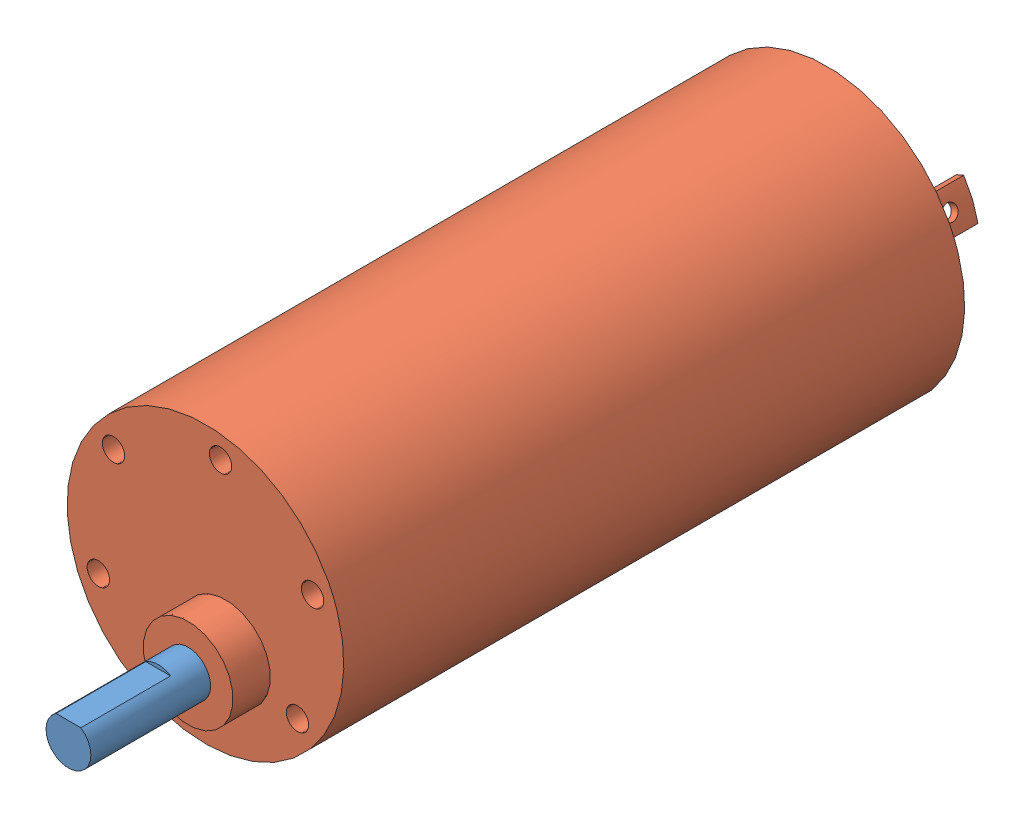
SolidWorks assembly 装配体1, configuration 默认. Lengths in mm.
Overall size (48.35 48.35 112).
2 component instances, 2 part files, 2 mates.
Components (placement in the parent):
- 电机输出轴-1: 电机输出轴 [默认] at (23.3279 -27.8279 -67.5811) size (6 6 36)
- 电机-1: 电机 [默认] at (20.6466 -21.3618 -52.5811) x (0.923728 0.383049 0) z (0 0 -1) size (37 37 96)
Mates (geometry in assembly coordinates):
- 同心1: concentric anti-aligned: cylinder of 电机输出轴-1 through (23.3279 -27.8279 -31.5811) axis (0 0 -1) radius 3; cylinder of 电机-1 through (23.3279 -27.8279 -5.5902) axis (0 0 -1) radius 3
- 重合2: coincident anti-aligned: plane of 电机输出轴-1 through (23.3279 -27.8279 -67.5811) normal (0 0 -1); plane of 电机-1 through (23.3279 -27.8279 -67.5811) normal (0 0 1)
